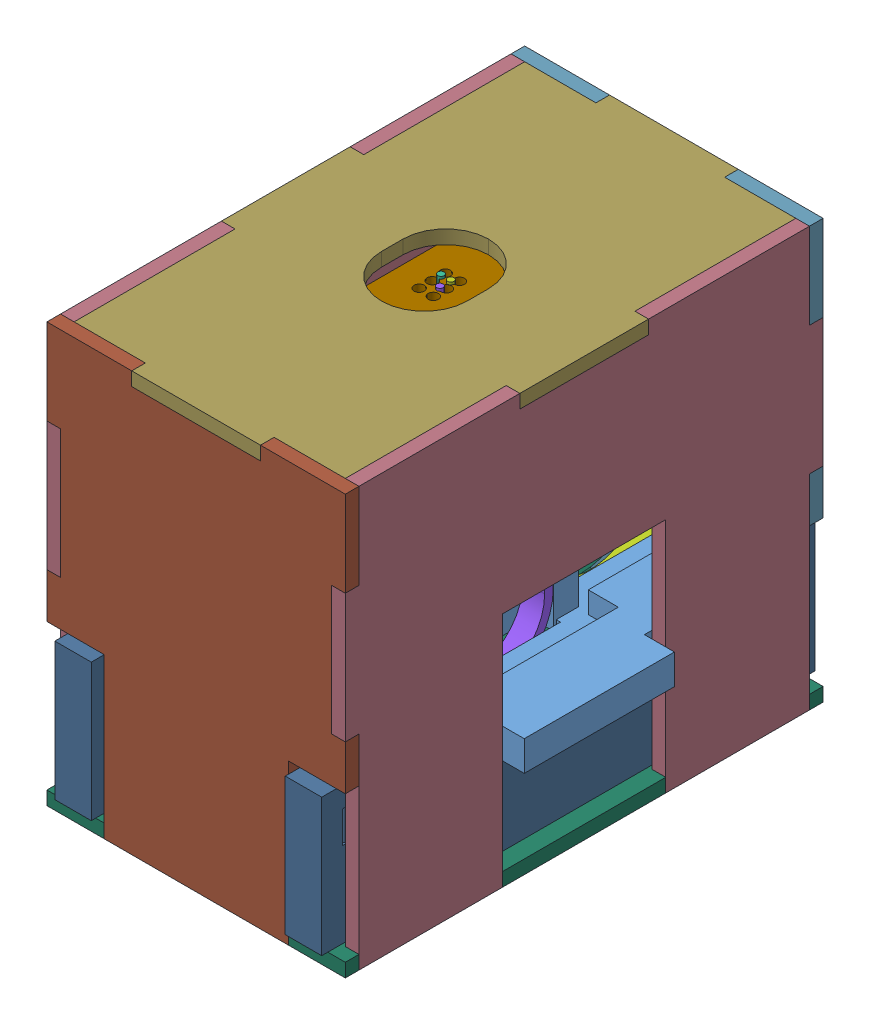
SolidWorks assembly x6Assembly, configuration Default. Lengths in mm.
Overall size (76.6 97.65 115.4).
22 component instances, 15 part files, 49 mates.
Components (placement in the parent):
- SixBasePart-1: SixBasePart [Default] at (51.6649 53.2498 75.0652) size (76.6 52 105)
- ServoMotor-1: ServoMotor [Default] at (87.5648 64.7882 128.8297) x (0 1 0) z (0 0 1) size (32 28.15 12)
- spur gear_am-1: spur gear_am [Metric - Spur gear 2M 10T 20PA 2FW ---S10N75H50L5N] at (56.7748 76.7648 147.5036) x (1 0 0) z (0 0.972443 -0.233139) size (2 22.98 24)
- rack spur rectangular_am-1: rack spur rectangular_am [Metric - Rack-spur - rectangular 2M 20PA 3FW 2PH 25L---SAll] at (58.7748 75.9817 135.0508) x (0 -1 0) z (-1 0 0) size (25 4 3)
- loop-1: loop [Default] at (56.7748 50.9817 147.5036) x (0 1 0) z (0 0 -1) size (53.8 5 28.8)
- RPServoAssy-1: RPServoAssy [Default] at (84.5163 53.0891 104.1993) x (1 0 0) z (0 1 0) size (28.15 32.3 55.59) (hidden)
  - spur gear_am-1: spur gear_am [Metric - Spur gear 2M 10T 20PA 2FW ---S10N75H50L5N] at (-18.7416 -7.9206 23.6757) x (-1 0 0) z (0 -0.356651 -0.934238) size (2 22.98 24)
  - rack spur rectangular_am-1: rack spur rectangular_am [Metric - Rack-spur - rectangular 2M 20PA 3FW 2PH 25L---SAll] at (-20.7416 -19.3498 7.8364) x (0 -0.066207 0.997806) z (-1 0 0) size (25 4 3)
  - loop-1: loop [Default] at (-15.7416 -8.5795 33.606) x (0 0.066207 -0.997806) z (0 0.997806 0.066207) size (53.8 5 28.8)
  - ServoMotor-1: ServoMotor [Default] at (10.0485 10.7533 11.699) x (0 0 1) z (0 -1 0) size (32 28.15 12)
- loopArmA-2: loopArmA [Default] at (54.5549 61.4419 77.4636) x (0 1 0) z (0 0 1) size (76.8 6.09 48.03)
- loopArmB-2: loopArmB [Default] at (61.8549 61.4419 77.4636) x (0 1 0) z (0 0 1) size (76.8 6.09 48.03)
- loopArmC-2: loopArmC [Default] at (68.8549 86.4419 112.5036) x (0 -1 0) z (0 0 -1) size (76.8 13.34 28.8)
- Top Cover-1: Top Cover [Default] at (51.1073 122.2648 101.7896) size (16.08 20.5 105)
- Feet-1: Feet [Default] at (87.0049 52.5648 60.2036) x (0 0 1) z (0 -1 0) size (115 8.5 32)
- Feet-2: Feet [Default] at (24.4049 52.5648 164.8036) x (0 0 -1) z (0 -1 0) size (115 8.5 32)
- BoxBackFront-1: BoxBackFront [Holey] at (20.9299 31.9648 165.0036) x (1 0 0) z (0 -1 0) size (69.55 3.17 97.65)
- BoxRoof-1: BoxRoof [Default] at (45.7049 123.2648 125.0036) size (69.55 3.17 111.35)
- BoxSides-1: BoxSides [Default] at (90.4799 31.9648 60.0036) x (0 0 1) z (0 -1 0) size (111.35 3.17 97.65)
- BoxSides-2: BoxSides [Default] at (20.9299 31.9648 165.0036) x (0 0 -1) z (0 -1 0) size (111.35 3.17 97.65)
- BoxBack-1: BoxBack [Default] at (90.4799 31.9648 60.0036) x (-1 0 0) z (0 -1 0) size (69.55 3.17 97.65)
- Box Base-1: Box Base [Default] at (20.9299 28.7898 56.8286) x (0 0 1) z (-1 0 0) size (111.35 3.17 69.55)
Mates (geometry in assembly coordinates):
- Coincident1: coincident anti-aligned: plane of SixBasePart-1 through (54.7049 59.7648 95.0036) normal (0 1 0); plane of ServoMotor-1 through (76.9248 59.7648 153.5036) normal (0 -1 0)
- Distance1: distance = 2 mm anti-aligned: plane of SixBasePart-1 through (71.4248 54.7648 75.0652) normal (-1 0 0); plane of ServoMotor-1 through (69.4248 71.2648 147.5036) normal (1 0 0)
- Coincident3: coincident aligned: cylinder of ServoMotor-1 through (56.7748 76.7648 147.5036) axis (1 0 0) radius 2.5; circle of spur gear_am-1
- Coincident4: coincident aligned: plane of ServoMotor-1 through (56.7748 76.7648 147.5036) normal (-1 0 0); plane of spur gear_am-1 through (56.7748 76.7648 147.5036) normal (-1 0 0)
- Coincident5: coincident aligned: plane of rack spur rectangular_am-1 through (61.7748 68.8367 135.1036) normal (0 0 1); plane of loop-1 through (61.7748 50.9817 135.1036) normal (0 0 1)
- Coincident6: coincident aligned: plane of rack spur rectangular_am-1 through (61.7748 75.9817 139.0508) normal (1 0 0); plane of loop-1 through (61.7748 50.9817 147.5036) normal (1 0 0)
- Coincident7: coincident aligned: line of rack spur rectangular_am-1 through (61.7748 75.9817 135.1036) axis (-1 0 0); line of loop-1 through (61.7748 75.9817 135.1036) axis (-1 0 0)
- Coincident8: coincident anti-aligned: plane of spur gear_am-1 through (58.7748 76.7648 147.5036) normal (1 0 0); plane of rack spur rectangular_am-1 through (58.7748 75.9817 139.0508) normal (-1 0 0)
- Parallel1: parallel anti-aligned: plane of SixBasePart-1 through (61.7049 52.7648 162.1036) normal (0 0 -1); plane of loop-1 through (61.7748 50.9817 161.9036) normal (0 0 1)
- Width1: width anti-aligned: plane of loop-1 through (61.7748 50.9817 159.9036) normal (0 0 -1); plane of loop-1 through (61.7748 50.9817 135.1036) normal (0 0 1); plane of ServoMotor-1 through (63.1248 59.7648 153.5036) normal (0 0 1); plane of ServoMotor-1 through (69.4248 59.7648 141.5036) normal (0 0 -1)
- RackPinionMate1: rack pinion = 20 mm: line of loop-1 through (56.7748 50.9817 135.1036) axis (0 1 0); circle of spur gear_am-1
- Width2: width anti-aligned: plane of SixBasePart-1 through (49.7049 52.7648 132.9036) normal (0 0 1); plane of SixBasePart-1 through (61.7049 52.7648 162.1036) normal (0 0 -1); plane of loop-1 through (61.7748 50.9817 133.1036) normal (0 0 -1); plane of loop-1 through (61.7748 50.9817 161.9036) normal (0 0 1)
- Coincident9: coincident anti-aligned: plane of SixBasePart-1 through (54.7049 59.7648 95.0036) normal (0 1 0); plane of RPServoAssy-1/ServoMotor-1 through (76.4248 59.7648 118.1199) normal (0 -1 0)
- Distance2: distance = 2 mm anti-aligned: plane of SixBasePart-1 through (78.4248 54.7648 75.0652) normal (-1 0 0); plane of RPServoAssy-1/ServoMotor-1 through (76.4248 71.2648 112.1199) normal (1 0 0)
- Concentric2: concentric aligned: cylinder of loopArmC-2 through (56.8549 123.8419 112.5036) axis (0 -1 0) radius 0.75
- Parallel4: parallel aligned: plane of SixBasePart-1 through (63.7049 52.7648 130.0036) normal (1 0 0); plane of loopArmC-2 through (68.8549 86.4419 112.5036) normal (1 0 0)
- Concentric3: concentric aligned: cylinder of loopArmA-2 through (54.5549 118.3419 109.9636) axis (0 1 0) radius 0.75
- Parallel5: parallel aligned: plane of SixBasePart-1 through (56.7049 52.7648 60.0036) normal (1 0 0); plane of loopArmA-2 through (54.5549 61.4419 77.4636) normal (1 0 0)
- Parallel6: parallel anti-aligned: plane of SixBasePart-1 through (49.7049 52.7648 95.0036) normal (1 0 0); plane of loopArmB-2 through (56.8549 61.4419 77.4636) normal (-1 0 0)
- Concentric4: concentric anti-aligned: cylinder of loopArmB-2 through (56.8549 118.3419 109.9636) axis (0 1 0) radius 0.75
- Coincident18: coincident aligned: plane of loopArmB-2 through (56.8549 123.8419 109.9636) normal (0 1 0); plane of loopArmC-2 through (56.8549 123.8419 112.5036) normal (0 1 0)
- Coincident19: coincident aligned: circle of loopArmA-2; plane of loopArmB-2 through (56.8549 123.8419 109.9636) normal (0 1 0)
- Width3: width anti-aligned: plane of Top Cover-1 through (63.745 123.2648 101.7896) normal (1 0 0); plane of Top Cover-1 through (47.6649 123.2648 101.7896) normal (-1 0 0); plane of SixBasePart-1 through (49.7049 52.7648 95.0036) normal (-1 0 0); plane of SixBasePart-1 through (61.7049 52.7648 60.0036) normal (1 0 0)
- Coincident21: coincident aligned: plane of SixBasePart-1 through (54.7049 52.7648 165.0036) normal (0 0 1); plane of Top Cover-1 through (51.1073 123.2648 165.0036) normal (0 0 1)
- Coincident22: coincident anti-aligned: plane of SixBasePart-1 through (56.7049 104.7648 60.0036) normal (0 1 0); plane of Top Cover-1 through (51.1073 104.7648 101.7896) normal (0 -1 0)
- Coincident23: coincident aligned: plane of Feet-1 through (87.0049 52.5648 60.2036) normal (1 0 0); plane of SixBasePart-1 through (87.0049 52.7648 165.0036) normal (1 0 0)
- Coincident24: coincident anti-aligned: plane of SixBasePart-1 through (54.7049 59.7648 95.0036) normal (0 1 0); plane of Feet-1 through (78.5049 59.7648 60.2036) normal (0 -1 0)
- Coincident25: coincident anti-aligned: plane of SixBasePart-1 through (56.7049 52.7648 60.0036) normal (0 0 -1); plane of Feet-1 through (78.5049 52.5648 60.0036) normal (0 0 1)
- Coincident26: coincident aligned: plane of SixBasePart-1 through (24.4049 52.7648 60.0036) normal (-1 0 0); plane of Feet-2 through (24.4049 52.5648 164.8036) normal (-1 0 0)
- Coincident27: coincident anti-aligned: plane of SixBasePart-1 through (56.7049 59.7648 60.0036) normal (0 1 0); plane of Feet-2 through (32.9049 59.7648 164.8036) normal (0 -1 0)
- Coincident28: coincident anti-aligned: plane of SixBasePart-1 through (54.7049 52.7648 165.0036) normal (0 0 1); plane of Feet-2 through (32.9049 52.5648 165.0036) normal (0 0 -1)
- Coincident29: coincident anti-aligned: plane of Top Cover-1 through (51.1073 123.2648 101.7896) normal (0 1 0); plane of BoxRoof-1 through (45.7049 123.2648 125.0036) normal (0 -1 0)
- Coincident30: coincident anti-aligned: plane of BoxBackFront-1 through (20.9299 31.9648 165.0036) normal (0 0 -1); plane of BoxRoof-1 through (45.7049 126.4398 165.0036) normal (0 0 1)
- Coincident32: coincident aligned: plane of BoxBackFront-1 through (20.9299 126.4398 168.1786) normal (0 1 0); plane of BoxRoof-1 through (45.7049 126.4398 125.0036) normal (0 1 0)
- Coincident33: coincident anti-aligned: plane of BoxRoof-1 through (87.3049 126.4398 125.0036) normal (1 0 0); plane of BoxSides-1 through (87.3049 31.9648 60.0036) normal (-1 0 0)
- Coincident34: coincident aligned: plane of BoxRoof-1 through (45.7049 126.4398 125.0036) normal (0 1 0); plane of BoxSides-1 through (87.3049 126.4398 60.0036) normal (0 1 0)
- Coincident35: coincident anti-aligned: plane of BoxBackFront-1 through (20.9299 31.9648 165.0036) normal (0 0 -1); plane of BoxSides-1 through (87.3049 31.9648 165.0036) normal (0 0 1)
- Coincident36: coincident aligned: plane of BoxBackFront-1 through (90.4799 31.9648 168.1786) normal (1 0 0); plane of BoxSides-1 through (90.4799 31.9648 60.0036) normal (1 0 0)
- Coincident37: coincident aligned: plane of BoxRoof-1 through (45.7049 126.4398 125.0036) normal (0 1 0); plane of BoxSides-2 through (24.1049 126.4398 165.0036) normal (0 1 0)
- Coincident38: coincident aligned: plane of BoxBackFront-1 through (20.9299 31.9648 168.1786) normal (-1 0 0); plane of BoxSides-2 through (20.9299 31.9648 165.0036) normal (-1 0 0)
- Coincident39: coincident anti-aligned: plane of BoxBackFront-1 through (20.9299 31.9648 165.0036) normal (0 0 -1); plane of BoxSides-2 through (24.1049 31.9648 165.0036) normal (0 0 1)
- Coincident40: coincident aligned: plane of BoxRoof-1 through (45.7049 126.4398 125.0036) normal (0 1 0); plane of BoxBack-1 through (90.4799 126.4398 56.8286) normal (0 1 0)
- Coincident41: coincident aligned: plane of BoxSides-2 through (20.9299 31.9648 165.0036) normal (-1 0 0); plane of BoxBack-1 through (20.9299 31.9648 56.8286) normal (-1 0 0)
- Coincident42: coincident anti-aligned: plane of BoxSides-2 through (24.1049 31.9648 60.0036) normal (0 0 -1); plane of BoxBack-1 through (90.4799 31.9648 60.0036) normal (0 0 1)
- Width4: width anti-aligned: plane of BoxSides-1 through (87.3049 31.9648 131.5036) normal (0 0 -1); plane of SixBasePart-1 through (87.3049 31.9648 93.5036) normal (0 0 1); plane of BoxSides-1 through (61.7049 52.7648 130.0036) normal (0 0 1); plane of SixBasePart-1 through (61.7049 52.7648 95.0036) normal (0 0 -1)
- Width5: width anti-aligned: plane of BoxBackFront-1 through (34.2049 31.9648 168.1786) normal (-1 0 0); plane of Feet-2 through (77.2049 31.9648 168.1786) normal (1 0 0); plane of BoxBackFront-1 through (32.9049 52.5648 164.8036) normal (1 0 0); plane of Feet-1 through (78.5049 52.5648 60.2036) normal (-1 0 0)
- Coincident45: coincident aligned: plane of BoxBackFront-1 through (20.9299 31.9648 168.1786) normal (0 0 1); plane of Box Base-1 through (20.9299 31.9648 168.1786) normal (0 0 1)
- Coincident47: coincident aligned: plane of BoxSides-1 through (90.4799 31.9648 60.0036) normal (1 0 0); plane of Box Base-1 through (90.4799 31.9648 56.8286) normal (1 0 0)
- Coincident48: coincident aligned: plane of BoxSides-1 through (87.3049 28.7898 60.0036) normal (0 -1 0); plane of Box Base-1 through (20.9299 28.7898 56.8286) normal (0 -1 0)
